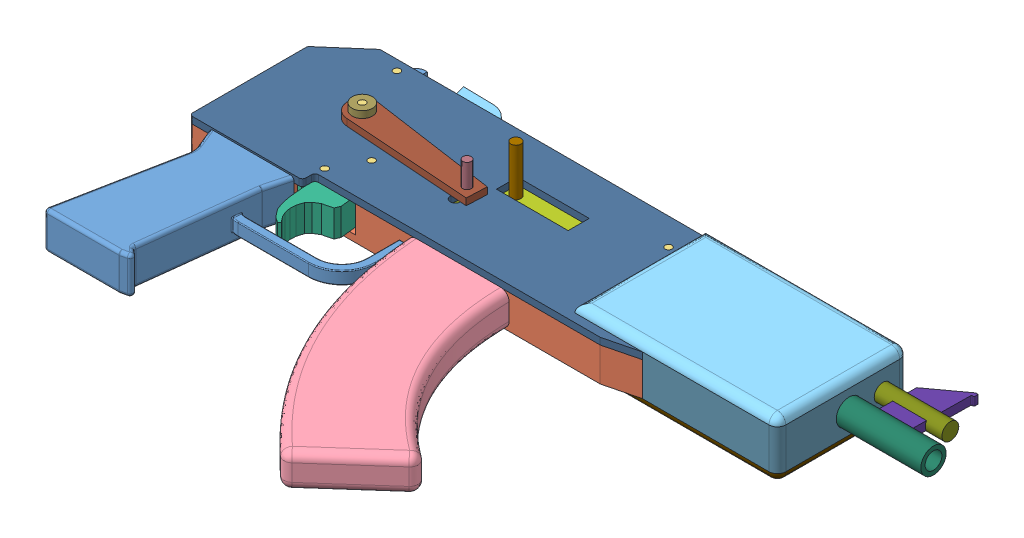
SolidWorks assembly Assembly, configuration Default. Lengths in mm.
Overall size (386 51 253.29).
27 component instances, 23 part files, 61 mates.
Components (placement in the parent):
- wheel-1: wheel [Default] at (-121.6948 73.4461 -11.4504) x (0.001182 0 -0.999999) z (0.999999 0 0.001182) size (29.07 12 29)
- FrameA-2: FrameA [Default] at (-137.6948 67.4461 -17.4504) size (256 20 90)
- pinA-1: pinA [Default] at (-121.6948 67.4461 -11.4504) size (4 24 4)
- toggle-1: toggle [Default] at (-148.8514 71.4461 -6.1025) x (0.048568 0 0.99882) z (-0.99882 0 0.048568) size (50.93 12 59.74)
- release-1: release [Default] at (-104.2706 77.9461 -33.5889) x (0.239382 0 0.970926) z (-0.970926 0 0.239382) size (89.38 12 35.83)
- trigger-1: trigger [Default] at (-106.2655 71.4461 47.4284) x (-0.400266 0 0.916399) z (-0.916399 0 -0.400266) size (40.84 16 41.76)
- Reciever-1: Reciever [Default] at (-82.1168 73.4461 0.2287) x (0.999771 0 0.021405) z (-0.021405 0 0.999771) size (140 12 50)
- reciever_swingybit-1: reciever_swingybit [Default] at (42.1054 80.9461 37.8963) x (-0.983668 0 -0.179993) z (-0.179993 0 0.983668) size (15 3 55)
- pinA-6: pinA [Default] at (49.3052 67.4461 -1.4504) x (0.950014 0 0.312208) z (-0.312208 0 0.950014) size (4 24 4)
- bolt-1: bolt [Default] at (-28.3432 73.4461 11.3822) x (0.532592 0 -0.846372) z (0.846372 0 0.532592) size (6 40 6)
- FrameB-2: FrameB [Default] at (-137.6948 87.4461 -17.4504) size (256 10 90)
- Lever-1: Lever [Default] at (-107.6948 91.4461 23.0496) x (0.999102 0 0.042367) z (-0.042367 0 0.999102) size (85.09 4 19.76)
- pin_fitting-1: pin_fitting [Default] at (-107.6948 99.4461 23.0496) x (-0.454579 0 -0.890706) z (-0.890706 0 0.454579) size (12 4 12)
- pinD-1: pinD [Default] at (-37.6474 71.4461 31.0244) x (-0.088182 0 -0.996104) z (0.996104 0 -0.088182) size (5 38 5)
- FrameC-1: FrameC [Default] at (95.3052 67.4461 60.0496) size (80 24 77.5)
- BarrelA-1: BarrelA [Default] at (165.3052 79.4461 17.5496) x (0 -0.999922 0.0125) z (0 0.0125 0.999922) size (15 60 15)
- BarrelB-1: BarrelB [Default] at (165.3052 79.4461 -2.4504) x (0 0.0125 0.999922) z (0 0.999922 -0.0125) size (10 50 10)
- sight-2: sight [Default] at (195.3052 77.0087 2.5789) x (1 0 0) z (0 0.0125 0.999922) size (21.5 5 45)
- SidingB-2: SidingB [Default] at (175.3052 67.4461 60.0496) x (-1 0 0) z (0 0 1) size (120 5 77.5)
- grip-1: grip [Default] at (-148.6948 68.4461 72.5496) size (118.13 22 97.5)
- pinC-1: pinC [Default] at (42.1054 73.4461 37.8963) x (0.169818 0 0.985475) z (-0.985475 0 0.169818) size (4 12 4)
- pinC-2: pinC [Default] at (-82.1168 73.4461 0.2287) size (4 12 4)
- pinA-7: pinA [Default] at (-92.9448 67.4461 60.0496) size (4 24 4)
- pinA-8: pinA [Default] at (-83.1948 67.4461 42.0496) size (4 24 4)
- pinB-2: pinB [Default] at (-107.6948 67.4461 23.0496) size (4 32 4)
- mag-1: mag [Default] at (-38.6948 67.6075 65.0496) size (128.74 26.05 148.29)
- SidingA-3: SidingA [Default] at (55.3052 91.4461 60.0496) size (120 5 77.5)
Mates (geometry in assembly coordinates):
- Concentric2: concentric aligned: cylinder of wheel-1 through (-121.6948 85.4461 -11.4504) axis (0 -1 0) radius 2.25; cylinder of wheel_pin-1 through (-121.6948 91.4461 -11.4504) axis (0 -1 0) radius 2
- Concentric10: concentric aligned: cylinder of release-1 through (-82.1168 80.9461 0.2287) axis (0 -1 0) radius 2.25; cylinder of Reciever-1 through (-82.1168 85.4461 0.2287) axis (0 -1 0) radius 2.125
- Distance2: distance = 7.5 mm anti-aligned: plane of reciever_swingybit-1 through (42.1054 80.9461 37.8963) normal (0 -1 0); plane of Reciever-1 through (-82.1168 73.4461 0.2287) normal (0 1 0)
- Concentric13: concentric anti-aligned: cylinder of Reciever-1 through (42.1054 85.4461 37.8963) axis (0 -1 0) radius 2.125; cylinder of reciever_swingybit-1 through (42.1054 77.9461 37.8963) axis (0 1 0) radius 2.25
- Concentric16: concentric anti-aligned: cylinder of reciever_swingybit-1 through (49.3052 77.9461 -1.4504) axis (0 1 0) radius 2.25; cylinder of wheel_pin-6 through (49.3052 91.4461 -1.4504) axis (0 -1 0) radius 2
- Concentric19: concentric aligned: cylinder of Reciever-1 through (-28.3432 85.4461 11.3822) axis (0 -1 0) radius 3; cylinder of reciver_handle-1 through (-28.3432 113.4461 11.3822) axis (0 -1 0) radius 3
- Coincident18: coincident aligned: plane of Reciever-1 through (-82.1168 73.4461 0.2287) normal (0 -1 0); plane of reciver_handle-1 through (-28.3432 73.4461 11.3822) normal (0 -1 0)
- Coincident22: coincident anti-aligned: plane of toggle-1 through (-148.8514 71.4461 -6.1025) normal (0 -1 0); plane of FrameA-2 through (-137.6948 71.4461 -17.4504) normal (0 1 0)
- Concentric22: concentric aligned: cylinder of wheel_pin-1 through (-121.6948 91.4461 -11.4504) axis (0 -1 0) radius 2; cylinder of FrameA-2 through (-121.6948 71.4461 -11.4504) axis (0 -1 0) radius 2
- Distance4: distance = 0.25 mm anti-aligned: plane of wheel-1 through (-116.2014 73.4461 -5.9439) normal (0 -1 0); plane of FrameA-2 through (-121.6948 73.1961 -11.4504) normal (0 1 0)
- Concentric23: concentric aligned: cylinder of wheel_pin-6 through (49.3052 91.4461 -1.4504) axis (0 -1 0) radius 2; cylinder of FrameA-2 through (49.3052 71.4461 -1.4504) axis (0 -1 0) radius 2
- Coincident27: coincident aligned: plane of wheel_pin-6 through (49.3052 67.4461 -1.4504) normal (0 -1 0); plane of FrameA-2 through (-137.6948 67.4461 -17.4504) normal (0 -1 0)
- Coincident28: coincident anti-aligned: plane of trigger-1 through (-106.2655 71.4461 47.4284) normal (0 -1 0); plane of FrameA-2 through (-137.6948 71.4461 -17.4504) normal (0 1 0)
- Concentric26: concentric aligned: cylinder of wheel_pin-6 through (49.3052 91.4461 -1.4504) axis (0 -1 0) radius 2; cylinder of FrameB-2 through (49.3052 91.4461 -1.4504) axis (0 -1 0) radius 2
- Coincident31: coincident aligned: plane of FrameA-2 through (-137.6948 67.4461 -17.4504) normal (0 -1 0); plane of wheel_pin-1 through (-121.6948 67.4461 -11.4504) normal (0 -1 0)
- Coincident32: coincident anti-aligned: plane of FrameB-2 through (-137.6948 91.4461 -17.4504) normal (0 1 0); plane of Lever-1 through (-107.6948 91.4461 23.0496) normal (0 -1 0)
- Coincident35: coincident anti-aligned: plane of Lever-1 through (-107.6948 95.4461 23.0496) normal (0 1 0); plane of pin_fitting-1 through (-107.6948 95.4461 23.0496) normal (0 -1 0)
- Concentric32: concentric aligned: cylinder of Lever-1 through (-37.6474 95.4461 31.0244) axis (0 -1 0) radius 2.5; cylinder of pinD-1 through (-37.6474 109.4461 31.0244) axis (0 -1 0) radius 2.5
- Coincident37: coincident anti-aligned: plane of FrameA-2 through (-137.6948 71.4461 -17.4504) normal (0 1 0); plane of pinD-1 through (-37.6474 71.4461 31.0244) normal (0 -1 0)
- Distance1: distance = 2 mm anti-aligned: plane of Reciever-1 through (-82.1168 73.4461 0.2287) normal (0 -1 0); plane of FrameA-2 through (-137.6948 71.4461 -17.4504) normal (0 1 0)
- Distance3: distance = 4.5 mm aligned: plane of release-1 through (-104.2706 77.9461 -33.5889) normal (0 1 0); plane of Reciever-1 through (-82.1168 73.4461 0.2287) normal (0 1 0)
- Coincident39: coincident aligned: plane of FrameA-2 through (-137.6948 67.4461 -17.4504) normal (0 -1 0); plane of FrameC-1 through (95.3052 67.4461 60.0496) normal (0 -1 0)
- Coincident40: coincident aligned: plane of FrameA-2 through (-137.6948 71.4461 -17.4504) normal (0 0 -1); plane of FrameC-1 through (95.3052 91.4461 -17.4504) normal (0 0 -1)
- Concentric36: concentric anti-aligned: cylinder of FrameC-1 through (165.3052 79.4461 17.5496) axis (1 0 0) radius 7.625; cylinder of BarrelA-1 through (225.3052 79.4461 17.5496) axis (-1 0 0) radius 7.5
- Coincident42: coincident anti-aligned: plane of FrameC-1 through (165.3052 79.4461 17.5496) normal (1 0 0); plane of BarrelA-1 through (165.3052 79.4461 17.5496) normal (-1 0 0)
- Distance7: distance = 0.125 mm anti-aligned: plane of BarrelA-1 through (205.4302 82.0709 17.5168) normal (-1 0 0); plane of sight-2 through (205.3052 82.1959 17.5152) normal (1 0 0)
- Coincident46: coincident anti-aligned: plane of BarrelA-1 through (165.3052 79.4461 17.5496) normal (0 -0.0125 -0.999922); plane of sight-2 through (185.3052 82.1959 17.5152) normal (0 0.0125 0.999922)
- Concentric37: concentric anti-aligned: cylinder of FrameC-1 through (165.3052 79.4461 -2.4504) axis (1 0 0) radius 5.125; cylinder of BarrelB-1 through (215.3052 79.4461 -2.4504) axis (-1 0 0) radius 5
- Coincident47: coincident anti-aligned: plane of FrameC-1 through (165.3052 79.4461 -2.4504) normal (1 0 0); plane of BarrelB-1 through (165.3052 79.4461 -2.4504) normal (-1 0 0)
- Coincident51: coincident anti-aligned: plane of FrameA-2 through (95.3052 71.4461 -17.4504) normal (1 0 0); plane of FrameC-1 through (95.3052 91.4461 60.0496) normal (-1 0 0)
- Distance5: distance = 0.125 mm anti-aligned: plane of sight-2 through (195.3052 82.0084 2.5164) normal (0 0.999922 -0.0125); plane of BarrelA-1 through (185.1802 82.0709 17.5168) normal (0 -0.999922 0.0125)
- Distance6: distance = 0.125 mm anti-aligned: plane of sight-2 through (195.3052 82.0084 2.5164) normal (0 0.999922 -0.0125); plane of BarrelB-1 through (185.1802 82.0084 -7.4829) normal (0 -0.999922 0.0125)
- Coincident57: coincident anti-aligned: plane of FrameC-1 through (95.3052 67.4461 60.0496) normal (0 -1 0); plane of SidingA-2 through (175.3052 67.4461 60.0496) normal (0 1 0)
- Coincident58: coincident aligned: line of FrameC-1 through (175.3052 67.4461 55.0496) axis (0 0 -1); line of SidingA-2 through (175.3052 67.4461 55.0496) axis (0 0 -1)
- Coincident59: coincident aligned: line of FrameC-1 through (170.3052 67.4461 -17.4504) axis (-1 0 0); line of SidingA-2 through (170.3052 67.4461 -17.4504) axis (-1 0 0)
- Coincident60: coincident anti-aligned: plane of FrameA-2 through (-93.6948 71.4461 72.5496) normal (0 0 1); plane of grip-1 through (-148.6948 90.4461 72.5496) normal (0 0 -1)
- Distance8: distance = 1 mm aligned: plane of grip-1 through (-148.6948 68.4461 72.5496) normal (0 -1 0); plane of FrameA-2 through (-137.6948 67.4461 -17.4504) normal (0 -1 0)
- Distance9: distance = 2 mm: line of FrameA-2 through (-100.6948 87.4461 72.5496) axis (0 -1 0); line of grip-1 through (-98.6948 88.4461 72.5496) axis (0 -1 0)
- Concentric38: concentric anti-aligned: cylinder of reciever_swingybit-1 through (42.1054 77.9461 37.8963) axis (0 1 0) radius 2.25; cylinder of pinC-1 through (42.1054 85.4461 37.8963) axis (0 -1 0) radius 2
- Concentric39: concentric aligned: cylinder of Reciever-1 through (42.1054 85.4461 37.8963) axis (0 -1 0) radius 2.125; cylinder of pinC-1 through (42.1054 85.4461 37.8963) axis (0 -1 0) radius 2
- Coincident61: coincident aligned: plane of Reciever-1 through (-82.1168 85.4461 0.2287) normal (0 1 0); plane of pinC-1 through (42.1054 85.4461 37.8963) normal (0 1 0)
- Concentric40: concentric aligned: cylinder of release-1 through (-82.1168 80.9461 0.2287) axis (0 -1 0) radius 2.25; cylinder of pinC-2 through (-82.1168 85.4461 0.2287) axis (0 -1 0) radius 2
- Concentric41: concentric aligned: cylinder of Reciever-1 through (-82.1168 85.4461 0.2287) axis (0 -1 0) radius 2.125; cylinder of pinC-2 through (-82.1168 85.4461 0.2287) axis (0 -1 0) radius 2
- Coincident62: coincident aligned: plane of Reciever-1 through (-82.1168 85.4461 0.2287) normal (0 1 0); plane of pinC-2 through (-82.1168 85.4461 0.2287) normal (0 1 0)
- Concentric42: concentric aligned: cylinder of trigger-1 through (-92.9448 87.4461 60.0496) axis (0 -1 0) radius 2.25; cylinder of pinA-7 through (-92.9448 91.4461 60.0496) axis (0 -1 0) radius 2
- Concentric43: concentric aligned: cylinder of FrameA-2 through (-92.9448 71.4461 60.0496) axis (0 -1 0) radius 2; cylinder of pinA-7 through (-92.9448 91.4461 60.0496) axis (0 -1 0) radius 2
- Coincident63: coincident aligned: plane of FrameA-2 through (-137.6948 67.4461 -17.4504) normal (0 -1 0); plane of pinA-7 through (-92.9448 67.4461 60.0496) normal (0 -1 0)
- Concentric44: concentric aligned: cylinder of release-1 through (-83.1948 80.9461 42.0496) axis (0 -1 0) radius 2.25; cylinder of pinA-8 through (-83.1948 91.4461 42.0496) axis (0 -1 0) radius 2
- Concentric45: concentric aligned: cylinder of FrameA-2 through (-83.1948 71.4461 42.0496) axis (0 -1 0) radius 2; cylinder of pinA-8 through (-83.1948 91.4461 42.0496) axis (0 -1 0) radius 2
- Coincident64: coincident aligned: plane of FrameA-2 through (-137.6948 67.4461 -17.4504) normal (0 -1 0); plane of pinA-8 through (-83.1948 67.4461 42.0496) normal (0 -1 0)
- Concentric46: concentric aligned: cylinder of toggle-1 through (-107.6948 83.4461 23.0496) axis (0 -1 0) radius 2.25; cylinder of pinB-2 through (-107.6948 99.4461 23.0496) axis (0 -1 0) radius 2
- Concentric47: concentric aligned: cylinder of FrameA-2 through (-107.6948 71.4461 23.0496) axis (0 -1 0) radius 2; cylinder of pinB-2 through (-107.6948 99.4461 23.0496) axis (0 -1 0) radius 2
- Coincident65: coincident aligned: plane of FrameA-2 through (-137.6948 67.4461 -17.4504) normal (0 -1 0); plane of pinB-2 through (-107.6948 67.4461 23.0496) normal (0 -1 0)
- Concentric48: concentric anti-aligned: cylinder of pin_fitting-1 through (-107.6948 95.4461 23.0496) axis (0 1 0) radius 2; cylinder of pinB-2 through (-107.6948 99.4461 23.0496) axis (0 -1 0) radius 2
- Coincident66: coincident aligned: plane of pin_fitting-1 through (-107.6948 99.4461 23.0496) normal (0 1 0); plane of pinB-2 through (-107.6948 99.4461 23.0496) normal (0 1 0)
- Concentric49: concentric aligned: cylinder of Lever-1 through (-107.6948 95.4461 23.0496) axis (0 -1 0) radius 2.25; cylinder of pinB-2 through (-107.6948 99.4461 23.0496) axis (0 -1 0) radius 2
- Coincident67: coincident anti-aligned: plane of FrameA-2 through (75.3052 71.4461 65.0496) normal (0 0 1); plane of mag-1 through (-38.6948 87.6075 65.0496) normal (0 0 -1)
- Coincident68: coincident aligned: line of grip-1 through (-38.6948 81.6961 65.0496) axis (0 -1 0); line of mag-1 through (-38.6948 82.6075 65.0496) axis (0 -1 0)
- Coincident69: coincident anti-aligned: plane of FrameC-1 through (95.3052 91.4461 60.0496) normal (0 1 0); plane of SidingA-3 through (55.3052 91.4461 60.0496) normal (0 -1 0)
- Coincident70: coincident anti-aligned: line of FrameC-1 through (175.3052 91.4461 55.0496) axis (0 0 -1); line of SidingA-3 through (175.3052 91.4461 -12.4504) axis (0 0 1)
- Coincident71: coincident anti-aligned: line of FrameC-1 through (170.3052 91.4461 -17.4504) axis (-1 0 0); line of SidingA-3 through (55.3052 91.4461 -17.4504) axis (1 0 0)
